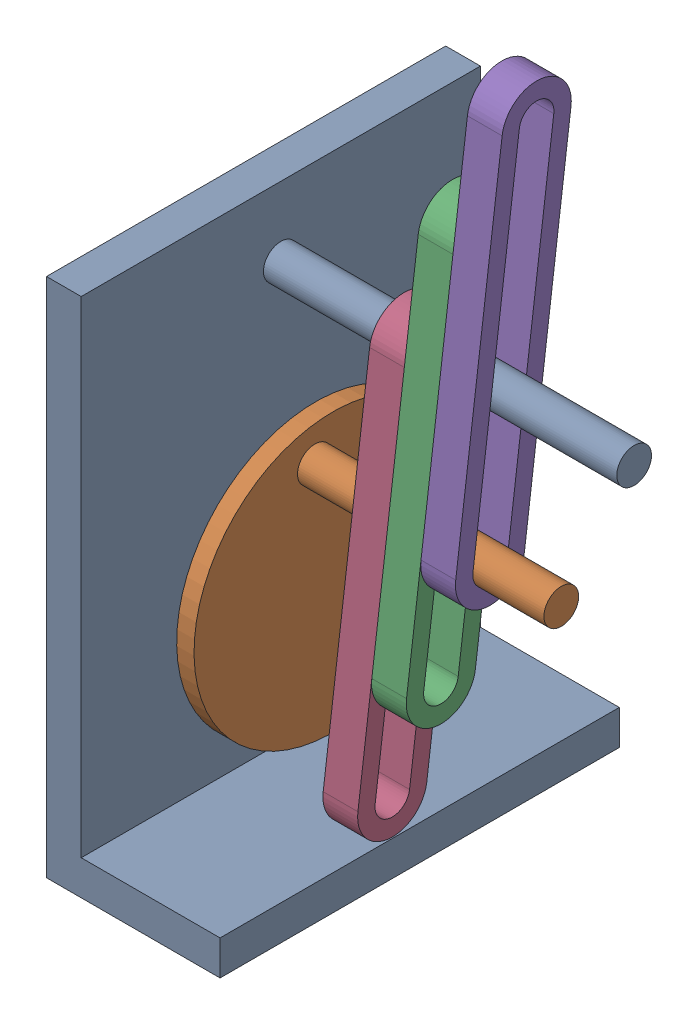
SolidWorks assembly SlotAssembly, configuration Default. Lengths in mm.
Overall size (111.78 204.88 115).
5 component instances, 3 part files, 13 mates.
Components (placement in the parent):
- BASE-1: BASE [Default] at (-47.6966 0.5615 82.2874) size (111.78 150 115)
- DISC-1: DISC [Default] at (-42.6966 119.6559 92.6727) x (1 0 0) z (0 0.173088 -0.984906) size (95.99 80 80)
- FOLLOWER-1: FOLLOWER [Default] at (-12.2026 32.8302 94.8325) x (1 0 0) z (0 0.127318 0.991862) size (10 125 20)
- FOLLOWER-2: FOLLOWER [Default] at (-22.2026 1.6195 98.8388) x (1 0 0) z (0 0.127318 0.991862) size (10 125 20)
- FOLLOWER-3: FOLLOWER [Default] at (-2.2026 65.3121 90.663) x (1 0 0) z (0 0.127318 0.991862) size (10 125 20)
Mates (geometry in assembly coordinates):
- Concentric1: concentric anti-aligned: cylinder of BASE-1 through (2.3034 60.5615 82.2874) axis (-1 0 0) radius 7.5; cylinder of DISC-1 through (-47.6966 60.5615 82.2874) axis (1 0 0) radius 7.5
- Coincident1: coincident aligned: plane of BASE-1 through (-47.6966 150.5615 139.7874) normal (-1 0 0); plane of DISC-1 through (-47.6966 60.5615 82.2874) normal (-1 0 0)
- Slot1: slot aligned: cylinder of DISC-1 through (48.2914 90.1087 87.48) axis (-1 0 0) radius 5; cylinder of FOLLOWER-1 through (17.7974 57.6267 91.6495) axis (-1 0 0) radius 5; cylinder of FOLLOWER-1 through (17.7974 161.7722 78.2811) axis (-1 0 0) radius 5
- Slot2: slot aligned: cylinder of BASE-1 through (64.0841 130.5615 82.2874) axis (-1 0 0) radius 5; cylinder of FOLLOWER-1 through (17.7974 161.7722 78.2811) axis (-1 0 0) radius 5; cylinder of FOLLOWER-1 through (17.7974 57.6267 91.6495) axis (-1 0 0) radius 5
- Width1: width anti-aligned: plane of DISC-1 through (48.2914 90.1087 87.48) normal (1 0 0); plane of FOLLOWER-1 through (-22.6966 60.5615 82.2874) normal (1 0 0); plane of DISC-1 through (7.7974 57.6267 91.6495) normal (-1 0 0); plane of FOLLOWER-1 through (17.7974 57.6267 91.6495) normal (1 0 0)
- Coincident2: coincident: line of FOLLOWER-1 through (7.7974 163.0454 88.1997) axis (0 -0.991862 0.127318); plane of FOLLOWER-2 through (7.7974 26.416 95.6558) normal (1 0 0)
- Coincident3: coincident: plane of FOLLOWER-1 through (17.7974 57.6267 91.6495) normal (1 0 0); line of FOLLOWER-3 through (17.7974 195.5274 84.0302) axis (0 -0.991862 0.127318)
- Slot3: slot aligned: cylinder of BASE-1 through (64.0841 130.5615 82.2874) axis (-1 0 0) radius 5; plane of FOLLOWER-3 through (27.7974 193.6176 69.1523) normal (0 0.127318 0.991862); cylinder of FOLLOWER-3 through (27.7974 90.1087 87.48) axis (-1 0 0) radius 5
- Slot4: slot aligned: plane of FOLLOWER-3 through (27.7974 193.6176 69.1523) normal (0 0.127318 0.991862); cylinder of DISC-1 through (48.2914 90.1087 87.48) axis (-1 0 0) radius 5; cylinder of FOLLOWER-3 through (27.7974 90.1087 87.48) axis (-1 0 0) radius 5
- Slot5: slot aligned: plane of FOLLOWER-2 through (7.7974 129.9249 77.3281) normal (0 0.127318 0.991862); cylinder of DISC-1 through (48.2914 90.1087 87.48) axis (-1 0 0) radius 5; cylinder of FOLLOWER-2 through (7.7974 26.416 95.6558) axis (-1 0 0) radius 5
- Slot6: slot aligned: plane of FOLLOWER-2 through (7.7974 129.9249 77.3281) normal (0 0.127318 0.991862); cylinder of BASE-1 through (64.0841 130.5615 82.2874) axis (-1 0 0) radius 5; cylinder of FOLLOWER-2 through (7.7974 26.416 95.6558) axis (-1 0 0) radius 5
- Concentric4: concentric aligned: cylinder of DISC-1 through (48.2914 90.1087 87.48) axis (-1 0 0) radius 5; cylinder of FOLLOWER-3 through (27.7974 90.1087 87.48) axis (-1 0 0) radius 5
- Concentric5: concentric aligned: cylinder of BASE-1 through (64.0841 130.5615 82.2874) axis (-1 0 0) radius 5; cylinder of FOLLOWER-2 through (7.7974 130.5615 82.2874) axis (-1 0 0) radius 5
